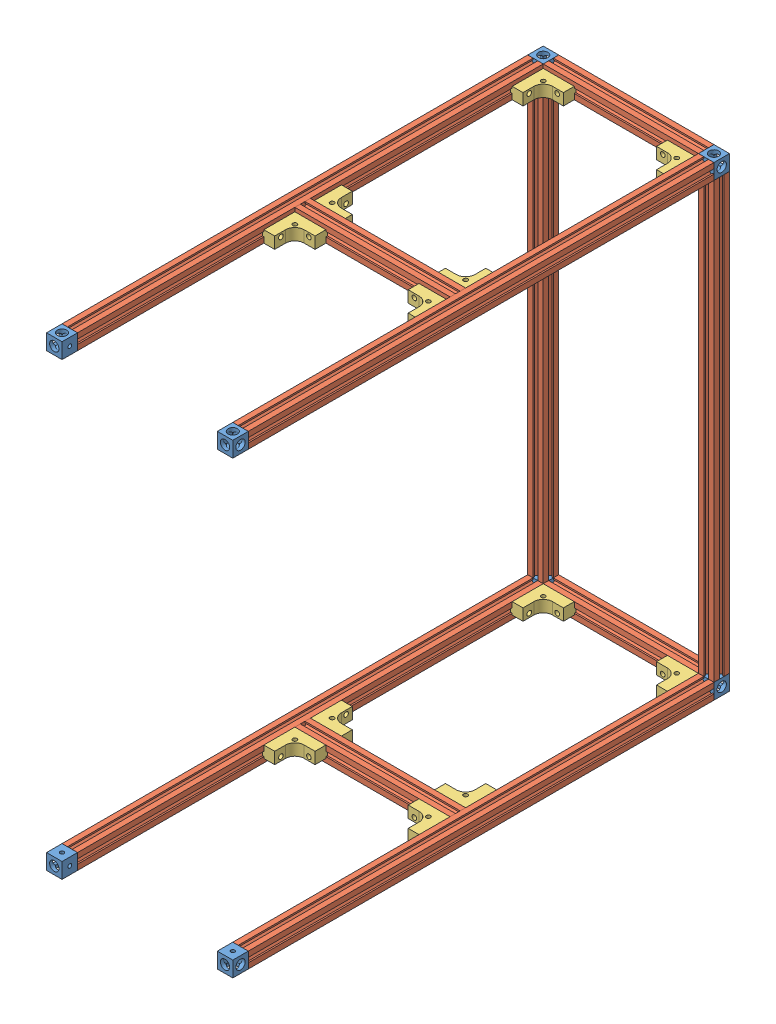
SolidWorks assembly BigRobotMakerBeamCentralFrame, configuration Default. Lengths in mm.
Overall size (120 300 320).
36 component instances, 3 part files, 9 mates.
Components (placement in the parent):
- BigRobotMakerBeamLeftFrame-1: BigRobotMakerBeamLeftFrame [Default] at (96.7704 -16.2623 -10.9933) size (120 10 320)
  - BigRobotMakerBeamFrame-1: BigRobotMakerBeamFrame [Default] at (45.5821 193.9563 421.287) size (10 10 320)
    - MakerBeam-cube-1: MakerBeam-cube [Default] at (-29.6175 -5.1709 14.1418) size (10 10 10)
    - Makerbeam50-1000mm-1: Makerbeam50-1000mm [300mm] at (-29.6175 -5.1709 -285.8582) size (10 10 300)
    - MakerBeam-cube-2: MakerBeam-cube [Default] at (-34.6175 -5.1709 -290.8582) x (0 0 -1) z (1 0 0) size (10 10 10)
  - BigRobotMakerBeamFrame-2: BigRobotMakerBeamFrame [Default] at (-99.2064 218.4029 421.287) x (0 1 0) z (0 0 1) size (10 10 320)
    - MakerBeam-cube-1: MakerBeam-cube [Default] at (-29.6175 -5.1709 14.1418) size (10 10 10)
    - Makerbeam50-1000mm-1: Makerbeam50-1000mm [300mm] at (-29.6175 -5.1709 -285.8582) size (10 10 300)
    - MakerBeam-cube-2: MakerBeam-cube [Default] at (-34.6175 -5.1709 -290.8582) x (0 0 -1) z (1 0 0) size (10 10 10)
  - Makerbeam50-1000mm-1: Makerbeam50-1000mm [100mm] at (10.9645 188.7853 130.4289) x (0 1 0) z (-1 0 0) size (10 10 100)
  - Bracket_L_Big_20x20_ForWindow-1: Bracket_L_Big_20x20_ForWindow [Default] at (-89.0355 183.7853 135.4289) x (0 0 1) z (0 1 0) size (21 21 7.5)
  - Bracket_L_Big_20x20_ForWindow-2: Bracket_L_Big_20x20_ForWindow [Default] at (10.9645 183.7853 135.4289) x (-1 0 0) z (0 1 0) size (21 21 7.5)
  - Makerbeam50-1000mm-2: Makerbeam50-1000mm [100mm] at (-89.0355 188.7853 290.4289) x (0 -1 0) z (1 0 0) size (10 10 100)
  - Bracket_L_Big_20x20_ForWindow-3: Bracket_L_Big_20x20_ForWindow [Default] at (-89.0355 183.7853 295.4289) x (0 0 1) z (0 1 0) size (21 21 7.5)
  - Bracket_L_Big_20x20_ForWindow-4: Bracket_L_Big_20x20_ForWindow [Default] at (10.9645 183.7853 295.4289) x (-1 0 0) z (0 1 0) size (21 21 7.5)
  - Bracket_L_Big_20x20_ForWindow-5: Bracket_L_Big_20x20_ForWindow [Default] at (10.9645 191.2853 285.4289) x (-1 0 0) z (0 -1 0) size (21 21 7.5)
  - Bracket_L_Big_20x20_ForWindow-6: Bracket_L_Big_20x20_ForWindow [Default] at (-89.0355 191.2853 285.4289) x (0 0 -1) z (0 -1 0) size (21 21 7.5)
- BigRobotMakerBeamLeftFrame-2: BigRobotMakerBeamLeftFrame [Default] at (18.6994 71.3084 -10.9933) x (-1 0 0) z (0 0 1) size (120 10 320)
  - BigRobotMakerBeamFrame-1: BigRobotMakerBeamFrame [Default] at (45.5821 193.9563 421.287) size (10 10 320)
    - MakerBeam-cube-1: MakerBeam-cube [Default] at (-29.6175 -5.1709 14.1418) size (10 10 10)
    - Makerbeam50-1000mm-1: Makerbeam50-1000mm [300mm] at (-29.6175 -5.1709 -285.8582) size (10 10 300)
    - MakerBeam-cube-2: MakerBeam-cube [Default] at (-34.6175 -5.1709 -290.8582) x (0 0 -1) z (1 0 0) size (10 10 10)
  - BigRobotMakerBeamFrame-2: BigRobotMakerBeamFrame [Default] at (-99.2064 218.4029 421.287) x (0 1 0) z (0 0 1) size (10 10 320)
    - MakerBeam-cube-1: MakerBeam-cube [Default] at (-29.6175 -5.1709 14.1418) size (10 10 10)
    - Makerbeam50-1000mm-1: Makerbeam50-1000mm [300mm] at (-29.6175 -5.1709 -285.8582) size (10 10 300)
    - MakerBeam-cube-2: MakerBeam-cube [Default] at (-34.6175 -5.1709 -290.8582) x (0 0 -1) z (1 0 0) size (10 10 10)
  - Makerbeam50-1000mm-1: Makerbeam50-1000mm [100mm] at (10.9645 188.7853 130.4289) x (0 1 0) z (-1 0 0) size (10 10 100)
  - Bracket_L_Big_20x20_ForWindow-1: Bracket_L_Big_20x20_ForWindow [Default] at (-89.0355 183.7853 135.4289) x (0 0 1) z (0 1 0) size (21 21 7.5)
  - Bracket_L_Big_20x20_ForWindow-2: Bracket_L_Big_20x20_ForWindow [Default] at (10.9645 183.7853 135.4289) x (-1 0 0) z (0 1 0) size (21 21 7.5)
  - Makerbeam50-1000mm-2: Makerbeam50-1000mm [100mm] at (-89.0355 188.7853 290.4289) x (0 -1 0) z (1 0 0) size (10 10 100)
  - Bracket_L_Big_20x20_ForWindow-3: Bracket_L_Big_20x20_ForWindow [Default] at (-89.0355 183.7853 295.4289) x (0 0 1) z (0 1 0) size (21 21 7.5)
  - Bracket_L_Big_20x20_ForWindow-4: Bracket_L_Big_20x20_ForWindow [Default] at (10.9645 183.7853 295.4289) x (-1 0 0) z (0 1 0) size (21 21 7.5)
  - Bracket_L_Big_20x20_ForWindow-5: Bracket_L_Big_20x20_ForWindow [Default] at (10.9645 191.2853 285.4289) x (-1 0 0) z (0 -1 0) size (21 21 7.5)
  - Bracket_L_Big_20x20_ForWindow-6: Bracket_L_Big_20x20_ForWindow [Default] at (-89.0355 191.2853 285.4289) x (0 0 -1) z (0 -1 0) size (21 21 7.5)
- Makerbeam50-1000mm-1: Makerbeam50-1000mm [280mm] at (112.7349 -112.477 119.4356) x (1 0 0) z (0 1 0) size (10 10 280)
- Makerbeam50-1000mm-2: Makerbeam50-1000mm [280mm] at (2.7349 167.523 119.4356) x (1 0 0) z (0 -1 0) size (10 10 280)
Mates (geometry in assembly coordinates):
- Concentric1: concentric aligned: cylinder of BigRobotMakerBeamLeftFrame-2/BigRobotMakerBeamFrame-2/MakerBeam-cube-2 through (112.7349 -122.477 119.4356) axis (0 -1 0) radius 1.25; cylinder of Makerbeam50-1000mm-1 through (112.7349 167.523 119.4356) axis (0 -1 0) radius 1.25
- Coincident1: coincident anti-aligned: plane of BigRobotMakerBeamLeftFrame-2/BigRobotMakerBeamFrame-2/MakerBeam-cube-2 through (112.7349 -112.477 119.4356) normal (0 1 0); plane of Makerbeam50-1000mm-1 through (112.7349 -112.477 119.4356) normal (0 -1 0)
- Coincident2: coincident aligned: plane of BigRobotMakerBeamLeftFrame-2/BigRobotMakerBeamFrame-2/MakerBeam-cube-2 through (107.7349 -122.477 114.4356) normal (0 0 -1); plane of Makerbeam50-1000mm-1 through (107.7349 167.523 114.4356) normal (0 0 -1)
- Coincident3: coincident anti-aligned: plane of BigRobotMakerBeamLeftFrame-1/BigRobotMakerBeamFrame-1/MakerBeam-cube-2 through (117.7349 167.523 114.4356) normal (0 -1 0); plane of Makerbeam50-1000mm-1 through (112.7349 167.523 119.4356) normal (0 1 0)
- Concentric2: concentric aligned: cylinder of BigRobotMakerBeamLeftFrame-1/BigRobotMakerBeamFrame-1/MakerBeam-cube-2 through (112.7349 167.523 119.4356) axis (0 -1 0) radius 1.25; cylinder of Makerbeam50-1000mm-1 through (112.7349 167.523 119.4356) axis (0 -1 0) radius 1.25
- Coincident4: coincident aligned: plane of BigRobotMakerBeamLeftFrame-1/BigRobotMakerBeamFrame-1/MakerBeam-cube-2 through (117.7349 167.523 114.4356) normal (0 0 -1); plane of Makerbeam50-1000mm-1 through (107.7349 167.523 114.4356) normal (0 0 -1)
- Coincident5: coincident anti-aligned: plane of BigRobotMakerBeamLeftFrame-1/BigRobotMakerBeamFrame-2/MakerBeam-cube-2 through (2.7349 167.523 119.4356) normal (0 -1 0); plane of Makerbeam50-1000mm-2 through (2.7349 167.523 119.4356) normal (0 1 0)
- Concentric3: concentric aligned: cylinder of BigRobotMakerBeamLeftFrame-1/BigRobotMakerBeamFrame-2/MakerBeam-cube-2 through (2.7349 177.523 119.4356) axis (0 1 0) radius 1.25; cylinder of Makerbeam50-1000mm-2 through (2.7349 -112.477 119.4356) axis (0 1 0) radius 1.25
- Coincident6: coincident aligned: plane of BigRobotMakerBeamLeftFrame-1/BigRobotMakerBeamFrame-2/MakerBeam-cube-2 through (7.7349 177.523 114.4356) normal (0 0 -1); plane of Makerbeam50-1000mm-2 through (1.2349 -112.477 114.4356) normal (0 0 -1)
